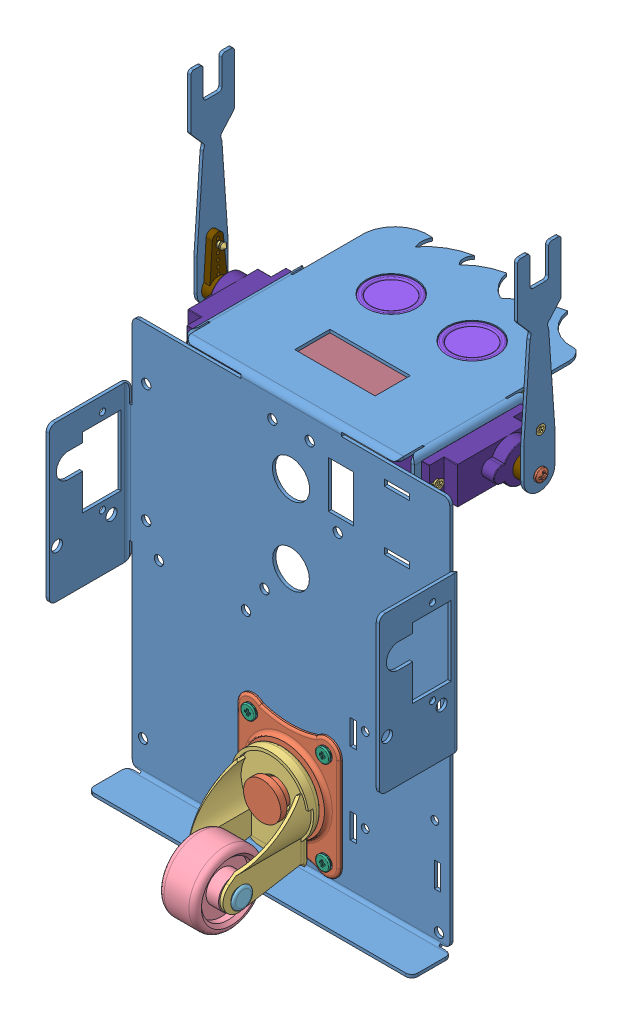
SolidWorks assembly MS_OL_AR, configuration Predeterminado. Lengths in mm.
Overall size (109.16 188.83 107.08).
60 component instances, 21 part files, 19 mates.
Components (placement in the parent):
- DYOR_OLED_MetalSheet_Arms-1: DYOR_OLED_MetalSheet_Arms [Predeterminado] at (88.2075 -136.9981 129.8829) size (107.01 129.16 94.63)
- CA-1: CA [Predeterminado] at (0.6637 3.5515 -8.7925) size (33 45.94 42.59)
  - Caster Wheel-1: Caster Wheel [Default] at (194.2283 -297.83 183.8938) x (0 1 0) z (-1 0 0) size (45.94 37.59 33)
    - caster holder-1: caster holder [Default] at (-24.0751 44.7184 29.5137) x (1 0 0) z (0 0 -1) size (39 9.27 33)
    - holder-1: holder [Default] at (-1.5751 42.9484 46.0137) x (0 0 1) z (1 0 0) size (25 28.07 31.31)
    - caster wheel-1: caster wheel [Default] at (-15.6961 19.9484 46.0137) x (0.997275 0.073773 0) z (0 0 1) size (23 23 14)
    - Part4-1: Part4 [Default] at (-15.6961 19.9484 55.0137) x (-0.978448 0.206495 0) z (0 0 -1) size (7 7 20)
  - M3x6 SelfTap Screw-1: M3x6 SelfTap Screw [Predeterminado] at (136.2146 -284.4051 140.6754) size (4.62 4.62 7)
  - M3x6 SelfTap Screw-2: M3x6 SelfTap Screw [Predeterminado] at (136.2146 -314.4051 140.6754) size (4.62 4.62 7)
  - M3x6 SelfTap Screw-3: M3x6 SelfTap Screw [Predeterminado] at (160.2146 -284.4051 140.6754) size (4.62 4.62 7)
  - M3x6 SelfTap Screw-4: M3x6 SelfTap Screw [Predeterminado] at (160.2146 -314.4051 140.6754) size (4.62 4.62 7)
- HC-SR04 Ping Sensor-1: HC-SR04 Ping Sensor [Default] at (148.9065 -202.2691 84.7391) x (0 0 -1) z (0 1 0) size (25.18 45 18.07)
  - PCB-1: PCB [Default] at origin size (20.5 45 1.75)
  - Transducer-1: Transducer [Default] at (0 -13 13.25) x (1 0 0) z (0 -1 0) size (15.88 12 15.88)
  - Transducer-2: Transducer [Default] at (0 13 13.25) x (1 0 0) z (0 -1 0) size (15.88 12 15.88)
  - 3 Pin Header 90 Degree-1: 3 Pin Header 90 Degree [Default] at (8.4275 0 -1.25) x (-1 0 0) z (0 -1 0) size (8 7.82 10)
  - 14 Pin SMT-1: 14 Pin SMT [Default] at (-0.35 -18.5 -0.85) x (0 -1 0) z (1 0 0) size (6 1.6 8.8)
  - 14 Pin SMT-2: 14 Pin SMT [Default] at (0 -0.3826 -0.85) x (1 0 0) z (0 1 0) size (6 1.6 8.8)
  - 14 Pin SMT-3: 14 Pin SMT [Default] at (0 17.5274 -0.85) x (1 0 0) z (0 1 0) size (6 1.6 8.8)
  - Cap1 SMT-1: Cap1 SMT [Default] at (-1.755 7.4774 -0.9689) x (0 1 0) z (-1 0 0) size (4.5 1.84 1.75)
  - Cap1 SMT-2: Cap1 SMT [Default] at (6.835 7.4774 -0.9689) x (0 1 0) z (-1 0 0) size (4.5 1.84 1.75)
  - Cap1 SMT-3: Cap1 SMT [Default] at (-6.835 7.4774 -0.9689) x (0 1 0) z (-1 0 0) size (4.5 1.84 1.75)
  - Cap1 SMT-4: Cap1 SMT [Default] at (4.295 7.4774 -0.9689) x (0 1 0) z (-1 0 0) size (4.5 1.84 1.75)
  - Cap1 SMT-5: Cap1 SMT [Default] at (1.755 7.4774 -0.9689) x (0 1 0) z (-1 0 0) size (4.5 1.84 1.75)
  - Cap1 SMT-6: Cap1 SMT [Default] at (-4.295 7.4774 -0.9689) x (0 1 0) z (-1 0 0) size (4.5 1.84 1.75)
  - HC-SR04 Crystal-1: HC-SR04 Crystal [Default] at (-8.3 0 1.75) x (0 -1 0) z (0 0 1) size (10 3.5 2.7)
- OLED_0.91_128x32-1: OLED_0.91_128x32 [Predeterminado] at (149.9973 -192.0291 110.045) x (1 0 0) z (0 1 0) size (38.3 12.1 11.46)
  - OLED_0.91_128x32.stp-1: OLED_0.91_128x32.stp [Predeterminado] at origin size (38.3 12.1 11.46)
    - OLED_0.91_128x32.stp-1: OLED_0.91_128x32.stp [Predeterminado] at origin size (38.3 12.1 2.57)
    - Pin Header 4 x 1 TH 2.54mm Pitch.stp-1: Pin Header 4 x 1 TH 2.54mm Pitch.stp [Predeterminado] at (-17.55 -3.81 -2.6) size (2.54 10.16 11.43)
    - RESC-0603.stp-1: RESC-0603.stp [Predeterminado] at (4.3 -5.3 0) x (1 0 0) z (0 0 -1) size (1.7 0.9 0.55)
    - RESC-0603.stp-2: RESC-0603.stp [Predeterminado] at (4.3 -3.8 0) x (1 0 0) z (0 0 -1) size (1.7 0.9 0.55)
    - RESC-0603.stp-3: RESC-0603.stp [Predeterminado] at (4.3 -2.3 0) x (1 0 0) z (0 0 -1) size (1.7 0.9 0.55)
    - RESC-0603.stp-4: RESC-0603.stp [Predeterminado] at (4.3 -0.8 0) x (1 0 0) z (0 0 -1) size (1.7 0.9 0.55)
    - RESC-0603.stp-5: RESC-0603.stp [Predeterminado] at (4.3 0.7 0) x (1 0 0) z (0 0 -1) size (1.7 0.9 0.55)
    - RESC-0603.stp-6: RESC-0603.stp [Predeterminado] at (4.3 2.2 0) x (1 0 0) z (0 0 -1) size (1.7 0.9 0.55)
    - RESC-0603.stp-7: RESC-0603.stp [Predeterminado] at (4.3 3.7 0) x (1 0 0) z (0 0 -1) size (1.7 0.9 0.55)
    - RESC-0603.stp-8: RESC-0603.stp [Predeterminado] at (4.3 5.2 0) x (1 0 0) z (0 0 -1) size (1.7 0.9 0.55)
    - RESC-0603.stp-9: RESC-0603.stp [Predeterminado] at (-1.4 -3.06 0) x (1 0 0) z (0 0 -1) size (1.7 0.9 0.55)
    - RESC-0603.stp-10: RESC-0603.stp [Predeterminado] at (-1.4 -1.56 0) x (1 0 0) z (0 0 -1) size (1.7 0.9 0.55)
    - RESC-0603.stp-11: RESC-0603.stp [Predeterminado] at (-1.4 -0.06 0) x (1 0 0) z (0 0 -1) size (1.7 0.9 0.55)
    - RESC-0603.stp-12: RESC-0603.stp [Predeterminado] at (-1.4 1.44 0) x (1 0 0) z (0 0 -1) size (1.7 0.9 0.55)
    - RESC-0603.stp-13: RESC-0603.stp [Predeterminado] at (-1.4 2.94 0) x (1 0 0) z (0 0 -1) size (1.7 0.9 0.55)
    - 2SD0601A.stp-1: 2SD0601A.stp [Predeterminado] at (-9.8 -1.3 -0.08) x (1 0 0) z (0 1 0) size (2.76 1.18 2.9)
- AR1-1: AR1 [Predeterminado] at (1.5666 2.6506 -1.7384) size (34.06 68.75 31.9)
  - sg90-2: sg90 [Default] at (126.818 -193.0635 98.9775) x (0 0 1) z (0 -1 0) size (31.9 29.9 11.8)
  - SG90 plastic Horn-2: SG90 plastic Horn [Default] at (97.368 -198.9635 104.8775) x (0 0.999767 0.021606) z (0 -0.021606 0.999767) size (19.4 4 7.07)
  - Arm-2: Arm [Predeterminado] at (94.368 -183.2019 59.6715) x (0 0 1) z (-1 0 0) size (14 67.85 1)
  - (M2_3_mm)_90116A007_METRIC 316 SS PAN HEAD PHILLIPS MACHINE SCREW-2: (M2_3_mm)_90116A007_METRIC 316 SS PAN HEAD PHILLIPS MACHINE SCREW [90116A007] at (97.368 -198.9635 104.8775) x (0 0 1) z (-1 0 0) size (4 4 4.68)
  - M2x6 SelfTap Screw-1: M2x6 SelfTap Screw [Predeterminado] at (93.868 -186.4635 104.8775) x (0 0.924225 0.381849) z (-1 0 0) size (3.4 3.28 6)
  - M2x6 SelfTap Screw-3: M2x6 SelfTap Screw [Predeterminado] at (107.418 -198.9635 123.8775) x (0 0.924225 0.381849) z (-1 0 0) size (3.4 3.28 6)
  - M2x6 SelfTap Screw-5: M2x6 SelfTap Screw [Predeterminado] at (107.418 -198.9635 96.5775) x (0 0.924225 0.381849) z (-1 0 0) size (3.4 3.28 6)
- AR2-1: AR2 [Predeterminado] at (-5.9481 2.6506 -1.7384) size (34.06 68.75 31.9)
  - sg90-1: sg90 [Default] at (175.3764 -204.8635 98.9775) x (0 0 1) z (0 1 0) size (31.9 29.9 11.8)
  - SG90 plastic Horn-1: SG90 plastic Horn [Default] at (204.8264 -198.9635 104.8775) x (0 0.999858 0.016879) z (0 0.016879 -0.999858) size (19.4 4 7.07)
  - Arm-1: Arm [Predeterminado] at (207.8264 -183.2019 150.0835) x (0 0 -1) z (1 0 0) size (14 67.85 1)
  - (M2_3_mm)_90116A007_METRIC 316 SS PAN HEAD PHILLIPS MACHINE SCREW-1: (M2_3_mm)_90116A007_METRIC 316 SS PAN HEAD PHILLIPS MACHINE SCREW [90116A007] at (204.8264 -198.9635 104.8775) x (0 0 -1) z (1 0 0) size (4 4 4.68)
  - M2x6 SelfTap Screw-2: M2x6 SelfTap Screw [Predeterminado] at (208.3264 -186.4635 104.8775) x (0 -0.924225 -0.381849) z (1 0 0) size (3.4 3.28 6)
  - M2x6 SelfTap Screw-4: M2x6 SelfTap Screw [Predeterminado] at (194.7764 -198.9635 123.8775) x (0 -0.924225 -0.381849) z (1 0 0) size (3.4 3.28 6)
  - M2x6 SelfTap Screw-6: M2x6 SelfTap Screw [Predeterminado] at (194.7764 -198.9635 96.5775) x (0 -0.924225 -0.381849) z (1 0 0) size (3.4 3.28 6)
Mates (geometry in assembly coordinates):
- Concéntrica329: concentric: circle of DYOR_OLED_MetalSheet_Arms-1; circle of ?
- Concéntrica330: concentric: circle of DYOR_OLED_MetalSheet_Arms-1; circle of ?
- Concéntrica331: concentric: circle of DYOR_OLED_MetalSheet_Arms-1; circle of HC-SR04 Ping Sensor-1/Transducer-1
- Paralelo105: parallel: plane of DYOR_OLED_MetalSheet_Arms-1 through (116.7346 -188.0191 128.8829) normal (0 0 -1); plane of HC-SR04 Ping Sensor-1/PCB-1 through (126.4065 -200.5191 94.9891) normal (0 0 1)
- Coincidente567: coincident: plane of DYOR_OLED_MetalSheet_Arms-1 through (116.7346 -188.5191 127.7391) normal (0 1 0); plane of HC-SR04 Ping Sensor-1/Transducer-1 through (161.9065 -188.5191 76.7991) normal (0 1 0)
- Coincidente568: coincident: plane of DYOR_OLED_MetalSheet_Arms-1 through (116.7346 -189.5191 127.7391) normal (0 -1 0); plane of OLED_0.91_128x32-1/OLED_0.91_128x32.stp-1/OLED_0.91_128x32.stp-1 through (148.7973 -189.5191 110.045) normal (0 1 0)
- Coincidente571: coincident: plane of DYOR_OLED_MetalSheet_Arms-1 through (187.519 -184.7905 69.0151) normal (1 0 0); plane of ? through (187.519 -204.1511 102.4556) normal (-1 0 0)
- Concéntrica332: concentric: circle of DYOR_OLED_MetalSheet_Arms-1; circle of ?
- Concéntrica333: concentric: circle of DYOR_OLED_MetalSheet_Arms-1; circle of ?
- Coincidente572: coincident: plane of DYOR_OLED_MetalSheet_Arms-1 through (116.7346 -188.0191 129.8829) normal (0 0 1); plane of CA-1/Caster Wheel-1/caster holder-1 through (148.8783 -251.0554 129.8829) normal (0 0 -1)
- Coincidente582: coincident: plane of DYOR_OLED_MetalSheet_Arms-1 through (184.3283 -190.4129 119.7391) normal (0 0 -1); plane of AR2-1/sg90-1 through (169.4283 -190.4129 119.7391) normal (0 0 1)
- Coincidente583: coincident: plane of DYOR_OLED_MetalSheet_Arms-1 through (185.3283 -121.5692 127.7391) normal (1 0 0); plane of AR2-1/sg90-1 through (185.3283 -202.2129 92.5391) normal (-1 0 0)
- Coincidente584: coincident: plane of DYOR_OLED_MetalSheet_Arms-1 through (184.3283 -202.2129 119.7391) normal (0 1 0); plane of AR2-1/sg90-1 through (169.4283 -202.2129 97.2391) normal (0 -1 0)
- Coincidente585: coincident: plane of DYOR_OLED_MetalSheet_Arms-1 through (112.4846 -185.9129 127.7391) normal (-1 0 0); plane of AR1-1/sg90-2 through (112.4846 -202.2129 124.4391) normal (1 0 0)
- Coincidente586: coincident: plane of DYOR_OLED_MetalSheet_Arms-1 through (113.4846 -190.4129 119.7391) normal (0 0 -1); plane of AR1-1/sg90-2 through (128.3846 -202.2129 119.7391) normal (0 0 1)
- Coincidente587: coincident: plane of DYOR_OLED_MetalSheet_Arms-1 through (113.4846 -202.2129 119.7391) normal (0 1 0); plane of AR1-1/sg90-2 through (128.3846 -202.2129 97.2391) normal (0 -1 0)
- Coincidente588: coincident: plane of DYOR_OLED_MetalSheet_Arms-1 through (135.8973 -189.5191 104.395) normal (1 0 0); plane of OLED_0.91_128x32-1/OLED_0.91_128x32.stp-1/OLED_0.91_128x32.stp-1 through (135.8973 -189.5791 104.395) normal (-1 0 0)
- Coincidente589: coincident: plane of DYOR_OLED_MetalSheet_Arms-1 through (161.6973 -189.5191 104.395) normal (0 0 1); plane of OLED_0.91_128x32-1/OLED_0.91_128x32.stp-1/OLED_0.91_128x32.stp-1 through (161.6973 -189.5791 104.395) normal (0 0 -1)
- Concéntrica334: concentric: circle of DYOR_OLED_MetalSheet_Arms-1; circle of CA-1/Caster Wheel-1/caster holder-1
